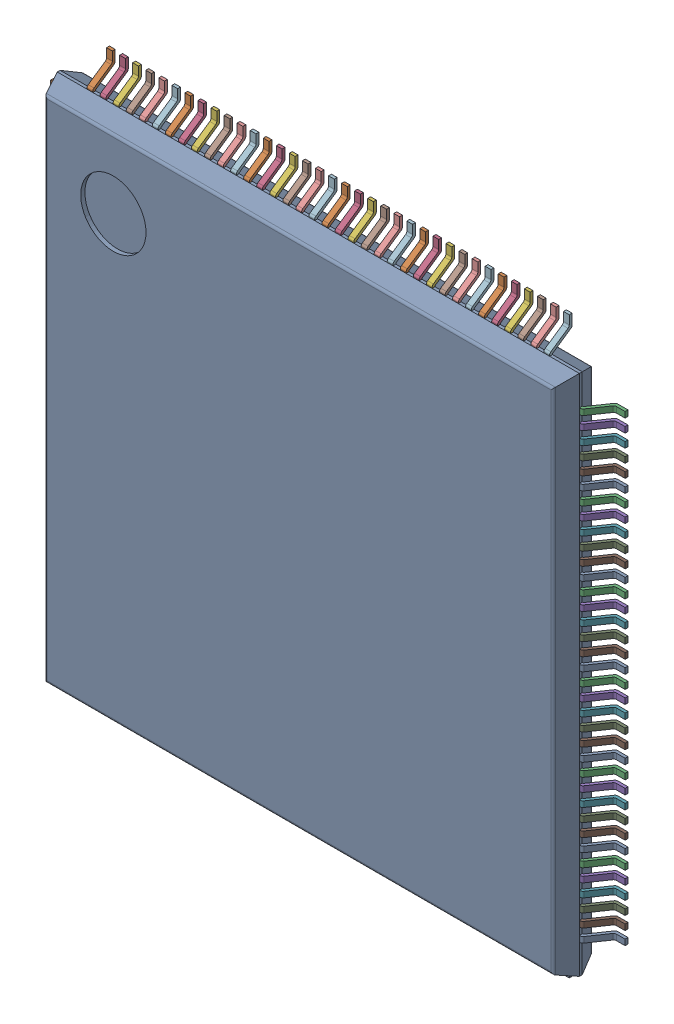
SolidWorks assembly IC2_1.step, configuration Default. Lengths in mm.
Overall size (22 22 1.6).
4 component instances, 3 part files, 0 mates.
Components (placement in the parent):
- 6348794688_1.step-11: 6348794688_1.step [Default] at (384.2997 276.4696 0) x (1 0 0) z (0 0 1) size (22 22 1.6)
  - Body-1211_1.step-21: Body-1211_1.step [Default] at origin size (20 20 1.5)
  - PinsArrayLR-1212_1.step-21: PinsArrayLR-1212_1.step [Default] at origin size (22 17.72 0.86)
  - PinsArrayTB_1.step-21: PinsArrayTB_1.step [Default] at origin size (17.72 22 0.86)
